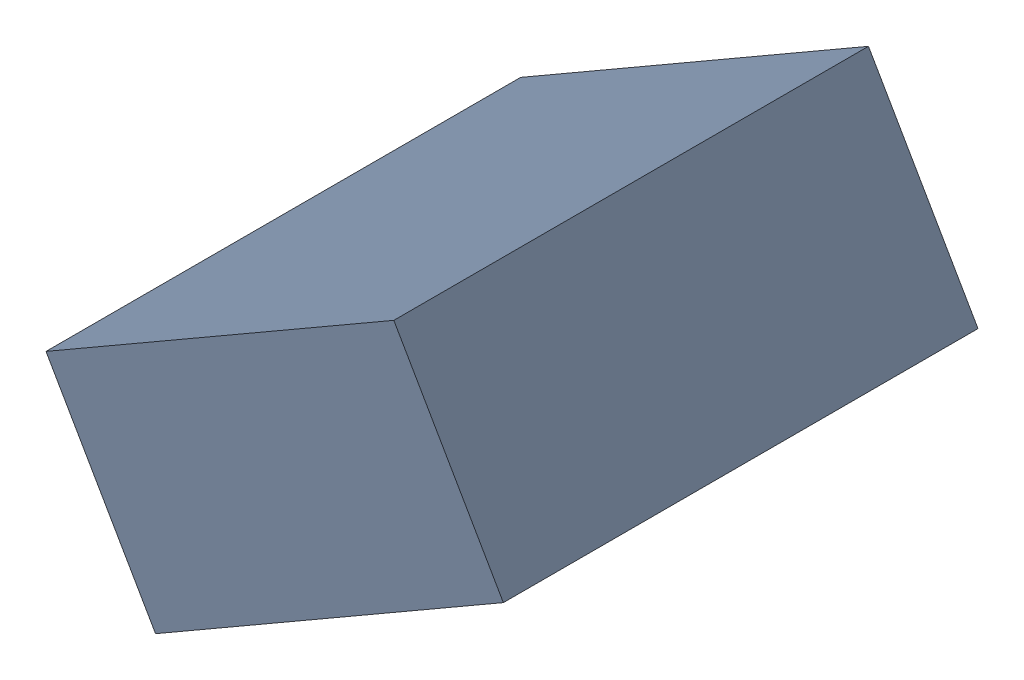
SolidWorks assembly C27_TDA2, configuration Standard. Lengths in mm.
Overall size (1.25 1.07 1.3).
2 component instances, 1 part files, 0 mates.
Components (placement in the parent):
- 885542920-1: 885542920 [Standard] at (49.2644 29.6666 0) size (1.25 1.07 1.3)
  - Extruded_24-1: Extruded_24 [Standard] at origin size (1.25 1.07 1.3)
